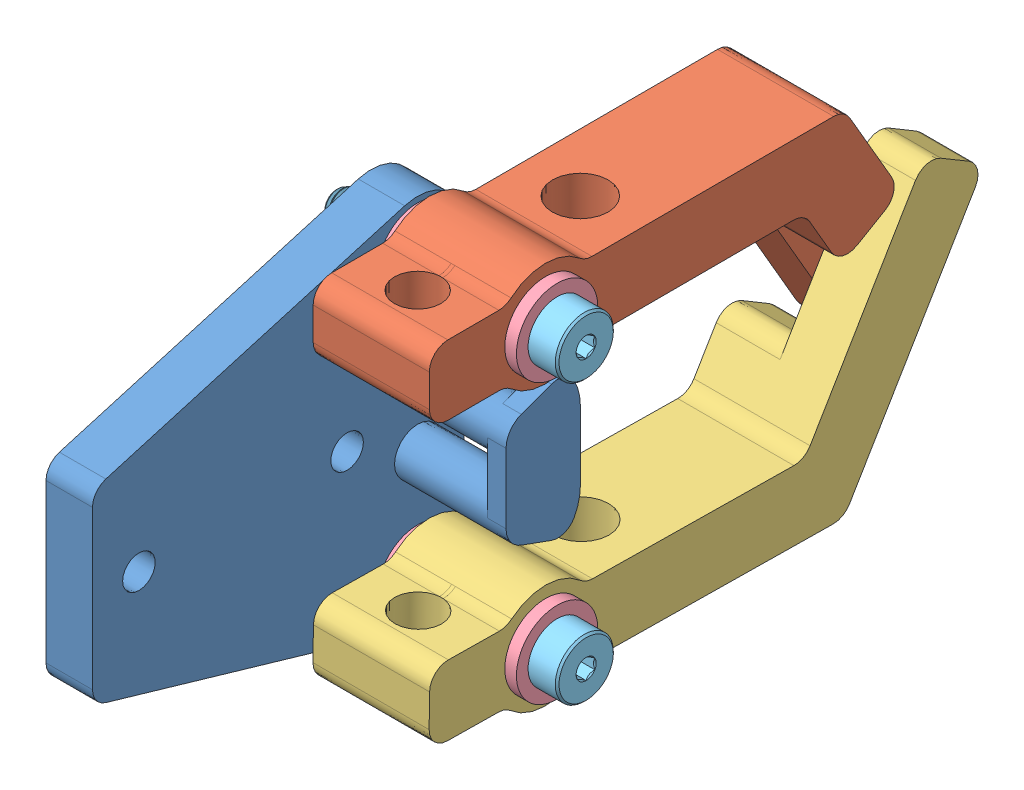
SolidWorks assembly MS-A-0013-02 Gripper, configuration Default. Lengths in mm.
Overall size (34.58 95.12 112.7).
9 component instances, 5 part files, 14 mates.
Components (placement in the parent):
- MS-P-0059-02 Gripper Claw Back Panel-1: MS-P-0059-02 Gripper Claw Back Panel [Default] at (6.6404 26.2861 24.2521) size (21.59 50.8 51.44)
- MS-P-0060-02 Top Claw-1: MS-P-0060-02 Top Claw [Default] at (8.2279 28.8223 33.7494) x (1 0 0) z (0 0.498542 0.866865) size (15.88 35.29 79.89)
- MS-P-0061-02 Bottom Claw-1: MS-P-0061-02 Bottom Claw [Default] at (24.1029 23.8576 33.5596) x (-1 0 0) z (0 -0.488579 0.87252) size (15.88 35.29 79.89)
- 6389K402_LIGHT DUTY DRY-RUNNING SLEEVE BEARING-1: 6389K402_LIGHT DUTY DRY-RUNNING SLEEVE BEARING [6389K402] at (25.6904 45.3361 24.2521) x (0 -0.989457 0.144828) z (0 -0.144828 -0.989457) size (11.11 6.35 11.11)
- 6389K402_LIGHT DUTY DRY-RUNNING SLEEVE BEARING-2: 6389K402_LIGHT DUTY DRY-RUNNING SLEEVE BEARING [6389K402] at (6.6404 7.2361 24.2521) x (0 0.381849 -0.924225) z (0 -0.924225 -0.381849) size (11.11 6.35 11.11)
- 6389K402_LIGHT DUTY DRY-RUNNING SLEEVE BEARING-3: 6389K402_LIGHT DUTY DRY-RUNNING SLEEVE BEARING [6389K402] at (25.6904 7.2361 24.2521) x (0 0.511677 -0.859178) z (0 0.859178 0.511677) size (11.11 6.35 11.11)
- 6389K402_LIGHT DUTY DRY-RUNNING SLEEVE BEARING-4: 6389K402_LIGHT DUTY DRY-RUNNING SLEEVE BEARING [6389K402] at (6.6404 45.3361 24.2521) x (0 0.825172 -0.564882) z (0 -0.564882 -0.825172) size (11.11 6.35 11.11)
- 91259A168_ALLOY STEEL SHOULDER SCREW-1: 91259A168_ALLOY STEEL SHOULDER SCREW [91259A168] at (29.6592 45.3361 24.2521) x (0 0 -1) z (1 0 0) size (7.94 7.94 34.58)
- 91259A168_ALLOY STEEL SHOULDER SCREW-2: 91259A168_ALLOY STEEL SHOULDER SCREW [91259A168] at (29.6592 7.2361 24.2521) x (0 0 -1) z (1 0 0) size (7.94 7.94 34.58)
Mates (geometry in assembly coordinates):
- Coincident2: coincident anti-aligned: circle of MS-P-0060 Top Claw-1; circle of 6389K402_LIGHT DUTY DRY-RUNNING SLEEVE BEARING-1
- Coincident3: coincident aligned: circle of MS-P-0060 Top Claw-1; circle of 6389K402_LIGHT DUTY DRY-RUNNING SLEEVE BEARING-4
- Concentric1: concentric aligned: circle of MS-P-0059 Gripper Claw Back Panel-1; circle of 6389K402_LIGHT DUTY DRY-RUNNING SLEEVE BEARING-4
- Coincident4: coincident anti-aligned: plane of MS-P-0059 Gripper Claw Back Panel-1 through (6.6404 45.3361 24.2521) normal (1 0 0); plane of 6389K402_LIGHT DUTY DRY-RUNNING SLEEVE BEARING-4 through (6.6404 45.3361 24.2521) normal (-1 0 0)
- Coincident5: coincident anti-aligned: circle of MS-P-0061 Bottom Claw-1; circle of 6389K402_LIGHT DUTY DRY-RUNNING SLEEVE BEARING-2
- Coincident6: coincident aligned: circle of MS-P-0061 Bottom Claw-1; circle of 6389K402_LIGHT DUTY DRY-RUNNING SLEEVE BEARING-3
- Concentric2: concentric anti-aligned: cylinder of MS-P-0059 Gripper Claw Back Panel-1 through (0.2904 7.2361 24.2521) axis (1 0 0) radius 2.7559; cylinder of 6389K402_LIGHT DUTY DRY-RUNNING SLEEVE BEARING-2 through (12.9904 7.2361 24.2521) axis (-1 0 0) radius 2.3813
- Coincident8: coincident anti-aligned: plane of MS-P-0059 Gripper Claw Back Panel-1 through (6.6404 45.3361 24.2521) normal (1 0 0); plane of 6389K402_LIGHT DUTY DRY-RUNNING SLEEVE BEARING-2 through (6.6404 7.2361 24.2521) normal (-1 0 0)
- GearMate1: gear = 4.7625 : 4.7625 mm: circle of 6389K402_LIGHT DUTY DRY-RUNNING SLEEVE BEARING-1; circle of 6389K402_LIGHT DUTY DRY-RUNNING SLEEVE BEARING-3
- GearMate3: gear = 14.2875 : 14.2875 mm: circle of MS-P-0060 Top Claw-1; circle of MS-P-0061 Bottom Claw-1
- Concentric3: concentric anti-aligned: circle of MS-P-0059 Gripper Claw Back Panel-1; circle of 91259A168_ALLOY STEEL SHOULDER SCREW-1
- Concentric4: concentric anti-aligned: circle of MS-P-0059 Gripper Claw Back Panel-1; circle of 91259A168_ALLOY STEEL SHOULDER SCREW-2
- Coincident10: coincident anti-aligned: plane of 6389K402_LIGHT DUTY DRY-RUNNING SLEEVE BEARING-3 through (25.6904 7.2361 24.2521) normal (1 0 0); plane of 91259A168_ALLOY STEEL SHOULDER SCREW-2 through (25.6904 3.2674 24.2521) normal (-1 0 0)
- Coincident11: coincident anti-aligned: plane of 6389K402_LIGHT DUTY DRY-RUNNING SLEEVE BEARING-1 through (25.6904 45.3361 24.2521) normal (1 0 0); plane of 91259A168_ALLOY STEEL SHOULDER SCREW-1 through (25.6904 41.3674 24.2521) normal (-1 0 0)
